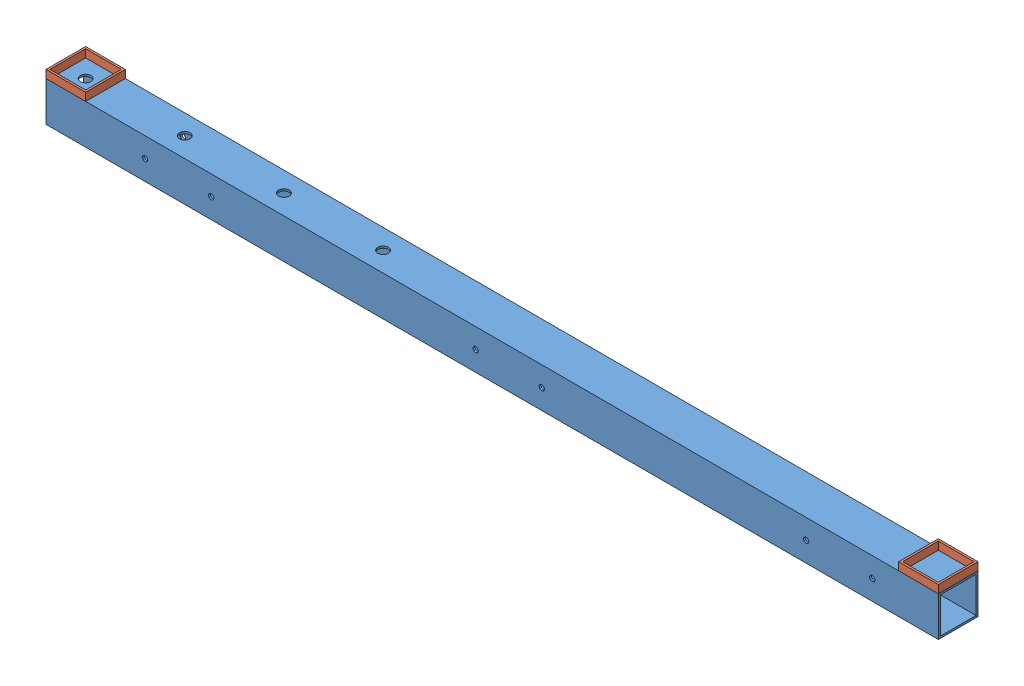
SolidWorks assembly Longeron675SupportAvecRehausseur, configuration Défaut. Lengths in mm.
Overall size (675 36 30).
3 component instances, 2 part files, 2 mates.
Components (placement in the parent):
- LongeronSuport675mm-1: LongeronSuport675mm [Défaut] at (-347.9795 -9 -2.6514) x (1 0 0) z (0 -1 0) size (675 30 30)
- rehausseur 6mm-1: rehausseur 6mm [Défaut] at (297.0205 21 -32.6514) size (30 6 30)
- rehausseur 6mm-2: rehausseur 6mm [Défaut] at (-347.9795 21 -32.6514) size (30 6 30)
Mates (geometry in assembly coordinates):
- Coïncidente1: coincident: point of LongeronSuport675mm-1; point of rehausseur 6mm-1
- Coïncidente2: coincident anti-aligned: plane of LongeronSuport675mm-1 through (327.0205 21 -2.6514) normal (0 1 0); plane of rehausseur 6mm-1 through (297.0205 21 -32.6514) normal (0 -1 0)
